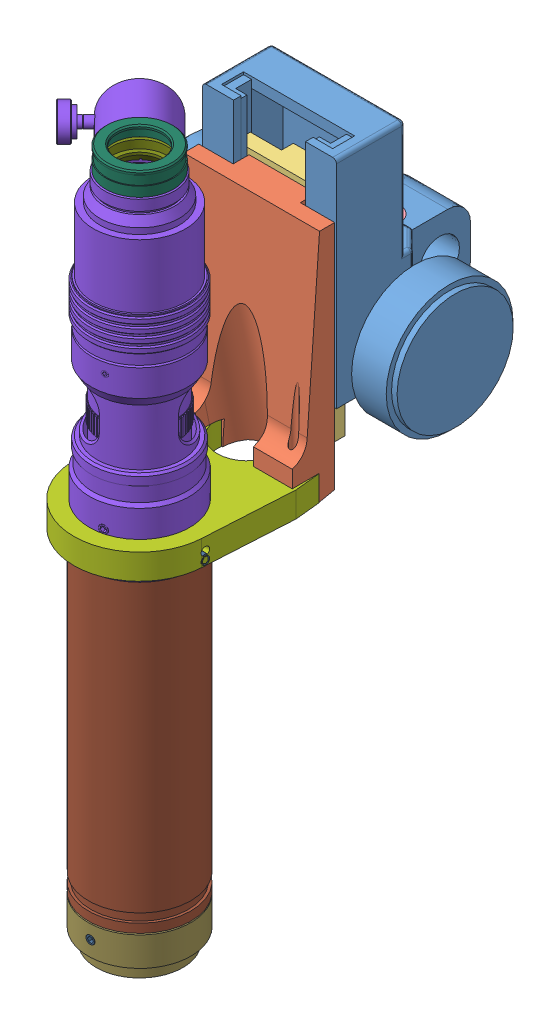
SolidWorks assembly Microscope Holder, configuration Default. Lengths in mm.
Overall size (113.5 273.92 151.76).
22 component instances, 16 part files, 41 mates.
Components (placement in the parent):
- Suporte da câmara-1: Suporte da câmara [Default] at (39.179 10.2391 110.382) size (107 90.6 73.6)
- Fixador câmara-1: Fixador câmara [Default] at (66.529 -16.9064 104.982) x (0 1 0) z (1 0 0) size (92.9 23.1 53.8)
- Corrediça da câmara-1: Corrediça da câmara [Default] at (34.629 76.8936 104.982) x (1 0 0) z (0 0 -1) size (37.4 85.5 10.5)
- Fixador inferior-1: Fixador inferior [Default] at (53.429 41.2391 65.132) x (0.972202 0 -0.234146) z (-0.234146 0 -0.972202) size (12.5 14 12.5)
- Fixador superior-1: Fixador superior [Default] at (53.429 10.2391 65.132) size (12.5 14 12.5)
- Tampa da corrediça-1: Tampa da corrediça [Default] at (26.479 9.7391 97.482) x (1 0 0) z (0 1 0) size (53.9 24.2 1.6)
- Anel fixação lente-1: Anel fixação lente [Default] at (53.229 -8.2397 161.632) x (0 0 1) z (0 -1 0) size (70 56 10)
- MVL6X3Z-Solidworks-1: MVL6X3Z-Solidworks [Default] at (46.5248 25.6964 134.8168) x (0 -1 0) z (-0.707107 0 -0.707107) size (134.62 45.26 83.25)
- socket button head screw_iso-1: socket button head screw_iso [ISO 7380 - M6 x 10 - 10N] at (53.429 10.2391 65.132) x (0 1 0) z (-0.985336 0 0.170626) size (13.3 10.5 10.5)
- socket set screw flat point_iso-3: socket set screw flat point_iso [ISO 4026 - M4 x 4-N] at (27.186 -13.2497 161.632) x (0.998348 0 -0.057463) z (0.057457 0.013867 0.998252) size (4 4 4)
- socket set screw flat point_iso-4: socket set screw flat point_iso [ISO 4026 - M4 x 4-N] at (79.2717 -16.4497 161.6392) x (-0.998348 0 -0.057463) z (0.052772 -0.395708 -0.916859) size (4 4 4)
- Adapter 1x-1: Adapter 1x [Default] at (53.229 -21.4147 161.632) x (-0.664073 0 -0.747667) z (-0.747667 0 0.664073) size (40.6 130.6 40.6)
- Coupler C Mount-1: Coupler C Mount [Default] at (53.229 -143.0147 161.632) x (0.999263 0 -0.03839) z (0 1 0) size (40.6 40.6 17.5)
- socket set screw flat point_iso-5: socket set screw flat point_iso [ISO 4026 - M4 x 4-N] at (54.0083 -149.0147 181.9171) x (-0.03839 0 -0.999263) z (0.588106 0.808468 -0.022594) size (4 4 4)
- socket head cap screw_iso-3: socket head cap screw_iso [ISO 4762 M4 x 12 - 12N] at (75.229 -18.7397 122.632) x (0 1 0) z (0.13306 0 0.991108) size (16 7 7)
- socket head cap screw_iso-4: socket head cap screw_iso [ISO 4762 M4 x 12 - 12N] at (31.229 -18.7397 122.632) x (0 1 0) z (0.363821 0 0.931469) size (16 7 7)
- socket countersunk head screw_iso-1: socket countersunk head screw_iso [ISO 10642 - M3 x 8 - 8N] at (37.679 9.7391 80.682) x (0 1 0) z (0.815348 0 -0.578971) size (8 5.54 5.54)
- socket countersunk head screw_iso-2: socket countersunk head screw_iso [ISO 10642 - M3 x 8 - 8N] at (68.979 9.7391 80.682) x (0 1 0) z (-0.65025 0 -0.75972) size (8 5.54 5.54)
- navitar-solid-model_1-60112-1: navitar-solid-model_1-60112 [Default] at (53.229 113.4085 161.632) x (0 -1 0) z (0.701845 0 -0.71233) size (12.96 26.75 26.75)
  - navitar-solid-model_1-60112.stp-1: navitar-solid-model_1-60112.stp [Default] at origin size (12.96 26.75 26.75)
    - 60120.stp-1: 60120.stp [Default] at origin size (8.92 26.75 26.75)
    - 60121.stp-1: 60121.stp [Default] at (6.08 0 0) x (1 0 0) z (0 0.999124 0.041848) size (6.88 25 25)
Mates (geometry in assembly coordinates):
- Coincident3: coincident anti-aligned: plane of Suporte da câmara-1 through (34.629 94.7391 98.682) normal (1 0 0); plane of Corrediça da câmara-1 through (34.629 76.8936 99.182) normal (-1 0 0)
- Coincident4: coincident anti-aligned: plane of Suporte da câmara-1 through (34.629 94.7391 104.982) normal (0 0 -1); plane of Corrediça da câmara-1 through (34.629 76.8936 104.982) normal (0 0 1)
- LimitDistance1: limit distance = 18.8455 mm aligned: plane of Corrediça da câmara-1 through (34.629 76.8936 99.182) normal (0 1 0); plane of Suporte da câmara-1 through (39.179 95.7391 110.382) normal (0 1 0)
- Coincident5: coincident anti-aligned: plane of Suporte da câmara-1 through (39.179 11.3391 110.382) normal (0 -1 0); plane of Tampa da corrediça-1 through (26.479 11.3391 97.482) normal (0 1 0)
- Coincident6: coincident anti-aligned: plane of Suporte da câmara-1 through (26.929 11.3391 73.282) normal (0 0 1); plane of Tampa da corrediça-1 through (32.479 11.3391 73.282) normal (0 0 -1)
- Distance3: distance = 0.45 mm aligned: plane of Tampa da corrediça-1 through (26.479 11.3391 97.482) normal (-1 0 0); plane of Suporte da câmara-1 through (26.929 95.7391 83.182) normal (-1 0 0)
- Concentric1: concentric aligned: cylinder of Suporte da câmara-1 through (53.429 58.9168 65.132) axis (0 -1 0) radius 6.25; cylinder of Fixador superior-1 through (53.429 24.2391 65.132) axis (0 -1 0) radius 6.25
- Coincident9: coincident aligned: plane of Suporte da câmara-1 through (39.179 10.2391 110.382) normal (0 -1 0); plane of Fixador superior-1 through (53.429 10.2391 65.132) normal (0 -1 0)
- Concentric2: concentric anti-aligned: cylinder of Suporte da câmara-1 through (53.429 58.9168 65.132) axis (0 -1 0) radius 6.25; cylinder of Fixador inferior-1 through (53.429 27.2391 65.132) axis (0 1 0) radius 6.25
- Coincident10: coincident aligned: plane of Suporte da câmara-1 through (72.429 41.2391 71.882) normal (0 1 0); plane of Fixador inferior-1 through (53.429 41.2391 65.132) normal (0 1 0)
- Concentric3: concentric aligned: cylinder of Fixador superior-1 through (53.429 14.2391 65.132) axis (0 -1 0) radius 4.5; cylinder of socket button head screw_iso-1 through (53.429 10.2391 65.132) axis (0 -1 0) radius 3
- Coincident11: coincident aligned: plane of Fixador superior-1 through (53.429 10.2391 65.132) normal (0 -1 0); plane of socket button head screw_iso-1 through (53.429 10.2391 65.132) normal (0 -1 0)
- Coincident12: coincident anti-aligned: plane of Fixador câmara-1 through (66.529 -16.9064 104.982) normal (0 0 -1); plane of Corrediça da câmara-1 through (34.629 76.8936 104.982) normal (0 0 1)
- Concentric4: concentric anti-aligned: cylinder of Fixador câmara-1 through (44.229 -1.1064 110.982) axis (0 0 -1) radius 1.6; cylinder of Corrediça da câmara-1 through (44.229 -1.1064 92.8181) axis (0 0 1) radius 2.25
- Parallel1: parallel aligned: plane of Suporte da câmara-1 through (79.929 95.7391 110.382) normal (1 0 0); plane of Fixador câmara-1 through (80.129 -16.9064 117.282) normal (1 0 0)
- Concentric8: concentric aligned: circle of Fixador câmara-1; cylinder of Anel fixação lente-1 through (75.229 -14.7397 122.632) axis (0 -1 0) radius 3.5
- Concentric9: concentric aligned: circle of Fixador câmara-1; cylinder of Anel fixação lente-1 through (31.229 -14.7397 122.632) axis (0 -1 0) radius 3.5
- Coincident16: coincident anti-aligned: plane of Fixador câmara-1 through (66.529 -8.2397 104.982) normal (0 -1 0); plane of Anel fixação lente-1 through (53.229 -8.2397 161.632) normal (0 1 0)
- Concentric10: concentric anti-aligned: cylinder of Anel fixação lente-1 through (53.229 -18.2397 161.632) axis (0 1 0) radius 19.85; cylinder of MVL6X3Z-Solidworks-1 through (53.229 -3.9649 161.632) axis (0 -1 0) radius 19.8247
- Coincident17: coincident anti-aligned: plane of Anel fixação lente-1 through (53.229 -18.2397 161.632) normal (0 -1 0); plane of MVL6X3Z-Solidworks-1 through (67.1004 -18.2397 149.3279) normal (0 1 0)
- Angle1: planar angle = 5.497787 rad aligned: plane of MVL6X3Z-Solidworks-1 through (5.9659 82.1157 126.187) normal (-0.707107 0 -0.707107); plane of Suporte da câmara-1 through (26.929 95.7391 83.182) normal (-1 0 0)
- Coincident21: coincident aligned: plane of Anel fixação lente-1 through (79.1861 -18.2397 163.1261) normal (0.998348 0 0.057463); plane of socket set screw flat point_iso-4 through (79.2717 -16.4497 161.6392) normal (0.998348 0 0.057463)
- Coincident22: coincident aligned: plane of Anel fixação lente-1 through (27.272 -18.2397 163.1261) normal (-0.998348 0 0.057463); plane of socket set screw flat point_iso-3 through (27.186 -13.2497 161.632) normal (-0.998348 0 0.057463)
- Tangent5: tangent: curve of Anel fixação lente-1; circle of socket set screw flat point_iso-3
- Concentric11: concentric anti-aligned: circle of MVL6X3Z-Solidworks-1; cylinder of Adapter 1x-1 through (53.229 -21.4147 161.632) axis (0 1 0) radius 20.3
- Coincident23: coincident anti-aligned: plane of MVL6X3Z-Solidworks-1 through (67.125 -21.4147 149.3061) normal (0 -1 0); plane of Adapter 1x-1 through (64.8171 -21.4147 174.6788) normal (0 1 0)
- Concentric12: concentric aligned: cylinder of Adapter 1x-1 through (53.229 -21.4147 161.632) axis (0 1 0) radius 12.7; cylinder of Coupler C Mount-1 through (53.229 -143.0147 161.632) axis (0 1 0) radius 17.45
- Coincident24: coincident anti-aligned: plane of Adapter 1x-1 through (66.7097 -143.0147 176.8097) normal (0 -1 0); plane of Coupler C Mount-1 through (35.7919 -143.0147 162.3019) normal (0 1 0)
- Concentric13: concentric anti-aligned: cylinder of Coupler C Mount-1 through (54.1888 -149.0147 186.6136) axis (-0.03839 0 -0.999263) radius 1.6; cylinder of socket set screw flat point_iso-5 through (54.4959 -149.0147 194.6077) axis (0.03839 0 0.999263) radius 2
- Tangent7: tangent aligned: cylinder of Coupler C Mount-1 through (53.229 -143.0147 161.632) axis (0 1 0) radius 20.3; plane of socket set screw flat point_iso-5 through (54.0083 -149.0147 181.9171) normal (0.03839 0 0.999263)
- Concentric14: concentric aligned: cylinder of Anel fixação lente-1 through (75.229 -14.7397 122.632) axis (0 -1 0) radius 3.5; cylinder of socket head cap screw_iso-3 through (75.229 -50.4897 122.632) axis (0 -1 0) radius 2
- Concentric15: concentric aligned: cylinder of Anel fixação lente-1 through (31.229 -14.7397 122.632) axis (0 -1 0) radius 3.5; cylinder of socket head cap screw_iso-4 through (31.229 -50.4897 122.632) axis (0 -1 0) radius 2
- Coincident25: coincident anti-aligned: plane of Anel fixação lente-1 through (31.229 -14.7397 122.632) normal (0 -1 0); plane of socket head cap screw_iso-4 through (27.9689 -14.7397 123.9054) normal (0 1 0)
- Coincident26: coincident anti-aligned: plane of Anel fixação lente-1 through (75.229 -14.7397 122.632) normal (0 -1 0); plane of socket head cap screw_iso-3 through (71.7602 -14.7397 123.0977) normal (0 1 0)
- Concentric16: concentric aligned: circle of Tampa da corrediça-1; cylinder of socket countersunk head screw_iso-2 through (68.979 9.7391 80.682) axis (0 -1 0) radius 1.5
- Concentric17: concentric aligned: circle of Tampa da corrediça-1; cylinder of socket countersunk head screw_iso-1 through (37.679 9.7391 80.682) axis (0 -1 0) radius 1.5
- Coincident27: coincident aligned: plane of Tampa da corrediça-1 through (26.479 9.7391 97.482) normal (0 -1 0); plane of socket countersunk head screw_iso-1 through (37.679 9.7391 80.682) normal (0 -1 0)
- Coincident28: coincident: plane of Tampa da corrediça-1 through (26.479 9.7391 97.482) normal (0 -1 0); point of socket countersunk head screw_iso-2
- Tangent8: tangent: curve of Anel fixação lente-1; circle of socket set screw flat point_iso-4
- Concentric18: concentric aligned: cylinder of MVL6X3Z-Solidworks-1 through (53.229 102.1055 161.632) axis (0 -1 0) radius 13.8811; cylinder of navitar-solid-model_1-60112-1/navitar-solid-model_1-60112.stp-1/60121.stp-1 through (53.229 104.3949 161.632) axis (0 -1 0) radius 12.5
- Coincident29: coincident anti-aligned: plane of MVL6X3Z-Solidworks-1 through (40.684 104.4931 158.2706) normal (0 1 0); plane of navitar-solid-model_1-60112-1/navitar-solid-model_1-60112.stp-1/60120.stp-1 through (62.3028 104.4931 170.5722) normal (0 -1 0)
